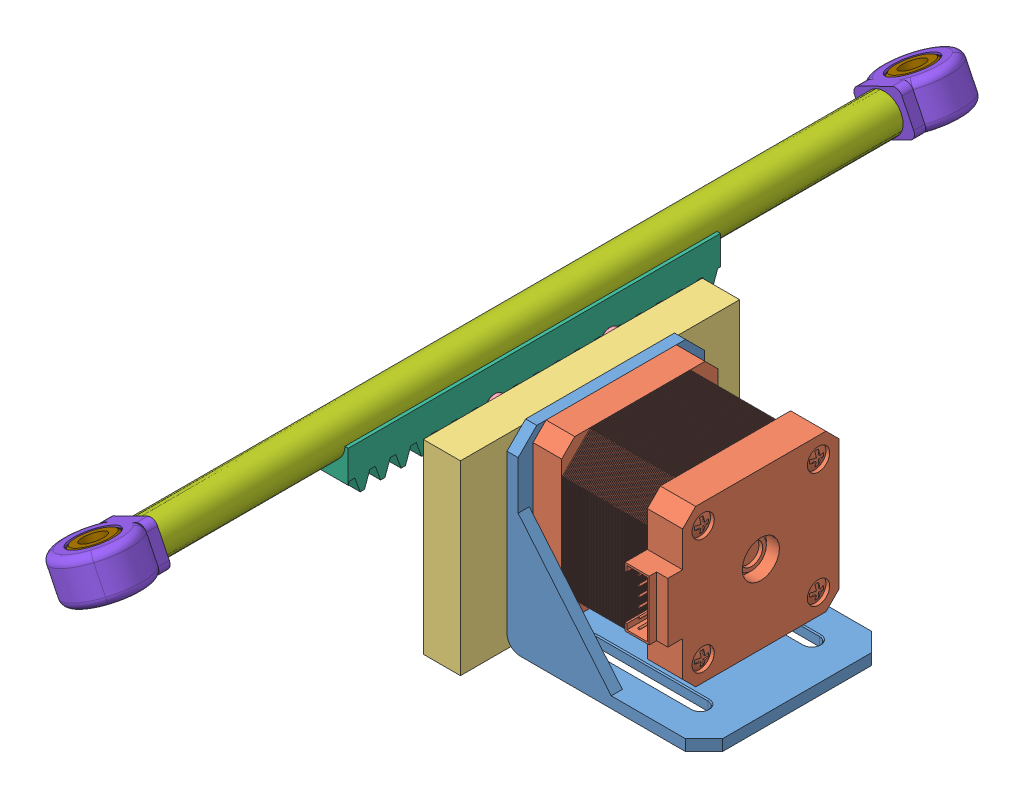
SolidWorks assembly steering!, configuration Default. Lengths in mm.
Overall size (92.11 68.68 248.43).
16 component instances, 9 part files, 28 mates.
Components (placement in the parent):
- steering mount!-1: steering mount! [NEMA17] at (-28.7683 28.591 65.5751) size (52.93 50.93 50)
- Nema 17HS4401-S-1: Nema 17HS4401-S [Varsayılan] at (61.5025 55.5202 65.5751) x (0 -1 0) z (-1 0 0) size (42 48 63.23)
- rackholder-1: rackholder [Default] at (8.3025 55.5202 65.5751) x (0 0 -1) z (1 0 0) size (75 50 10)
- socket head cap screw_am-5: socket head cap screw_am [B18.3.1M - 3 x 0.5 x 20 Hex SHCS -- 20NHX] at (5.3025 71.0202 81.0751) size (23 5.5 5.5)
- socket head cap screw_am-6: socket head cap screw_am [B18.3.1M - 3 x 0.5 x 20 Hex SHCS -- 20NHX] at (5.3025 71.0202 50.0751) size (23 5.5 5.5)
- socket head cap screw_am-7: socket head cap screw_am [B18.3.1M - 3 x 0.5 x 20 Hex SHCS -- 20NHX] at (5.3025 40.0202 50.0751) size (23 5.5 5.5)
- socket head cap screw_am-8: socket head cap screw_am [B18.3.1M - 3 x 0.5 x 20 Hex SHCS -- 20NHX] at (5.3025 40.0202 81.0751) size (23 5.5 5.5)
- spur gear_am-2: spur gear_am [Metric - Spur gear 1.5M 20T 20PA 12FW ---S20N75H50L5N] at (5.3025 55.5202 65.5751) x (-1 0 0) z (0 -0.832543 -0.553961) size (12 32.71 32.71)
- rack spur rectangular_am-2: rack spur rectangular_am [Metric - Rack-spur - rectangular 1.75M 20PA 12FW 10PH 100L---SAll] at (5.3025 80.5202 20.2306) x (0 0 1) z (1 0 0) size (100 11.75 12)
- Newrod-1: Newrod [Default] at (-0.6975 80.5202 170.2306) x (0 0 -1) z (0.901023 0.433771 0) size (200 10.2 10.2)
- myrodend-1: myrodend [Default] at (1.7555 75.4971 -25.6983) x (0.635392 0.310285 0.707107) z (-0.635392 -0.310285 0.707107) size (27.9 11.18 27.9)
  - housing-1: housing [Default] at origin size (27.9 11.61 27.9)
  - Ball-1: Ball [Default] at (-10 5.59 -10) x (0.999657 0 0.026198) z (-0.026198 0 0.999657) size (15 11.18 15)
- myrodend-2: myrodend [Default] at (1.7555 75.4971 166.1596) x (-0.635392 -0.310285 -0.707107) z (0.635392 0.310285 -0.707107) size (27.9 11.18 27.9)
  - housing-1: housing [Default] at origin size (27.9 11.61 27.9)
  - Ball-1: Ball [Default] at (-10 5.59 -10) x (0.999657 0 0.026198) z (-0.026198 0 0.999657) size (15 11.18 15)
Mates (geometry in assembly coordinates):
- Concentric1: concentric anti-aligned: cylinder of steering mount!-1 through (18.3025 71.0202 50.0751) axis (1 0 0) radius 1.75; cylinder of Nema 17HS4401-S-1 through (26.3025 71.0202 50.0751) axis (-1 0 0) radius 1.25
- Coincident1: coincident anti-aligned: plane of steering mount!-1 through (21.3025 76.5202 65.5751) normal (1 0 0); plane of Nema 17HS4401-S-1 through (21.3025 55.5202 65.5751) normal (-1 0 0)
- Concentric6: concentric anti-aligned: cylinder of Nema 17HS4401-S-1 through (19.3025 55.5202 65.5751) axis (1 0 0) radius 4.5; cylinder of rackholder-1 through (18.3025 55.5202 65.5751) axis (-1 0 0) radius 5
- Coincident6: coincident anti-aligned: plane of steering mount!-1 through (18.3025 76.5202 65.5751) normal (-1 0 0); plane of rackholder-1 through (18.3025 55.5202 65.5751) normal (1 0 0)
- Concentric8: concentric anti-aligned: cylinder of rackholder-1 through (18.3025 55.5202 65.5751) axis (-1 0 0) radius 5; cylinder of helical gear_3_am-3 through (-16.4475 55.5202 65.5751) axis (1 0 0) radius 2.5
- Distance1: distance = 1 mm anti-aligned: plane of helical gear_3_am-3 through (7.3025 55.5202 65.5751) normal (1 0 0); plane of rackholder-1 through (8.3025 55.5202 65.5751) normal (-1 0 0)
- Concentric9: concentric aligned: cylinder of rackholder-1 through (8.3025 71.0202 81.0751) axis (-1 0 0) radius 1.75; cylinder of socket head cap screw_am-5 through (-26.4475 71.0202 81.0751) axis (-1 0 0) radius 2.75
- Coincident8: coincident anti-aligned: plane of rackholder-1 through (8.3025 55.5202 65.5751) normal (-1 0 0); plane of socket head cap screw_am-5 through (8.3025 73.7702 81.0751) normal (1 0 0)
- Concentric10: concentric aligned: cylinder of rackholder-1 through (8.3025 71.0202 50.0751) axis (-1 0 0) radius 1.75; cylinder of socket head cap screw_am-6 through (-26.4475 71.0202 50.0751) axis (-1 0 0) radius 2.75
- Coincident9: coincident anti-aligned: plane of rackholder-1 through (8.3025 55.5202 65.5751) normal (-1 0 0); plane of socket head cap screw_am-6 through (8.3025 73.7702 50.0751) normal (1 0 0)
- Concentric11: concentric aligned: cylinder of rackholder-1 through (8.3025 40.0202 50.0751) axis (-1 0 0) radius 1.75; cylinder of socket head cap screw_am-7 through (-26.4475 40.0202 50.0751) axis (-1 0 0) radius 2.75
- Coincident10: coincident anti-aligned: plane of rackholder-1 through (8.3025 55.5202 65.5751) normal (-1 0 0); plane of socket head cap screw_am-7 through (8.3025 42.7702 50.0751) normal (1 0 0)
- Concentric12: concentric aligned: cylinder of rackholder-1 through (8.3025 40.0202 81.0751) axis (-1 0 0) radius 1.75; cylinder of socket head cap screw_am-8 through (-26.4475 40.0202 81.0751) axis (-1 0 0) radius 2.75
- Coincident11: coincident anti-aligned: plane of rackholder-1 through (8.3025 55.5202 65.5751) normal (-1 0 0); plane of socket head cap screw_am-8 through (8.3025 42.7702 81.0751) normal (1 0 0)
- Concentric14: concentric aligned: cylinder of Nema 17HS4401-S-1 through (-1.6975 55.5202 65.5751) axis (1 0 0) radius 2.5; cylinder of spur gear_am-2 through (-44.6975 55.5202 65.5751) axis (1 0 0) radius 2.5
- Distance3: distance = 5 mm aligned: plane of spur gear_am-2 through (-6.6975 55.5202 65.5751) normal (-1 0 0); plane of Nema 17HS4401-S-1 through (-1.6975 55.5202 65.5751) normal (-1 0 0)
- Coincident14: coincident aligned: plane of spur gear_am-2 through (-6.6975 55.5202 65.5751) normal (-1 0 0); plane of rack spur rectangular_am-1 through (-6.6975 43.8666 -70.4596) normal (-1 0 0)
- Parallel2: parallel anti-aligned: plane of rack spur rectangular_am-1 through (3.3025 25.8542 58.149) normal (0 -1 0)
- Parallel3: parallel aligned: plane of raCK-2 through (-6.6975 80.5202 20.2306) normal (0 1 0)
- Coincident18: coincident aligned: plane of spur gear_am-2 through (5.3025 55.5202 65.5751) normal (1 0 0); plane of raCK-2 through (5.3025 68.7702 20.2306) normal (1 0 0)
- Distance4: distance = 5 mm aligned: plane of rack spur rectangular_am-2 through (-6.6975 80.5202 20.2306) normal (0 1 0); plane of rackholder-1 through (18.3025 75.5202 103.0751) normal (0 1 0)
- Concentric15: concentric aligned: cylinder of raCK-2 through (-0.6975 80.5202 20.2306) axis (0 0 1) radius 5.1; cylinder of Newrod-1 through (-0.6975 80.5202 -29.7694) axis (0 0 1) radius 5.1
- Distance5: distance = 50 mm aligned: plane of Newrod-1 through (-0.6975 80.5202 170.2306) normal (0 0 1); plane of raCK-2 through (-6.6975 80.5202 120.2306) normal (0 0 1)
- Concentric16: concentric aligned: cylinder of Newrod-1 through (-0.6975 80.5202 -29.7694) axis (0 0 1) radius 3.25; cylinder of myrodend-1/housing-1 through (-0.6975 80.5202 -29.7694) axis (0 0 1) radius 3.25
- Concentric17: concentric anti-aligned: cylinder of Newrod-1 through (-0.6975 80.5202 -29.7694) axis (0 0 1) radius 3.25; cylinder of myrodend-2/housing-1 through (-0.6975 80.5202 170.2306) axis (0 0 -1) radius 3.25
- Coincident20: coincident aligned: plane of myrodend-1/housing-1 through (-3.1504 85.5432 -25.6983) normal (-0.438809 0.89858 0); plane of myrodend-2/housing-1 through (-3.1504 85.5432 166.1596) normal (-0.438809 0.89858 0)
- Coincident21: coincident anti-aligned: plane of Newrod-1 through (-0.6975 80.5202 170.2306) normal (0 0 1); plane of myrodend-2/housing-1 through (-0.6975 80.5202 170.2306) normal (0 0 -1)
- Coincident22: coincident anti-aligned: plane of Newrod-1 through (-0.6975 80.5202 -29.7694) normal (0 0 -1); plane of myrodend-1/housing-1 through (-0.6975 80.5202 -29.7694) normal (0 0 1)
